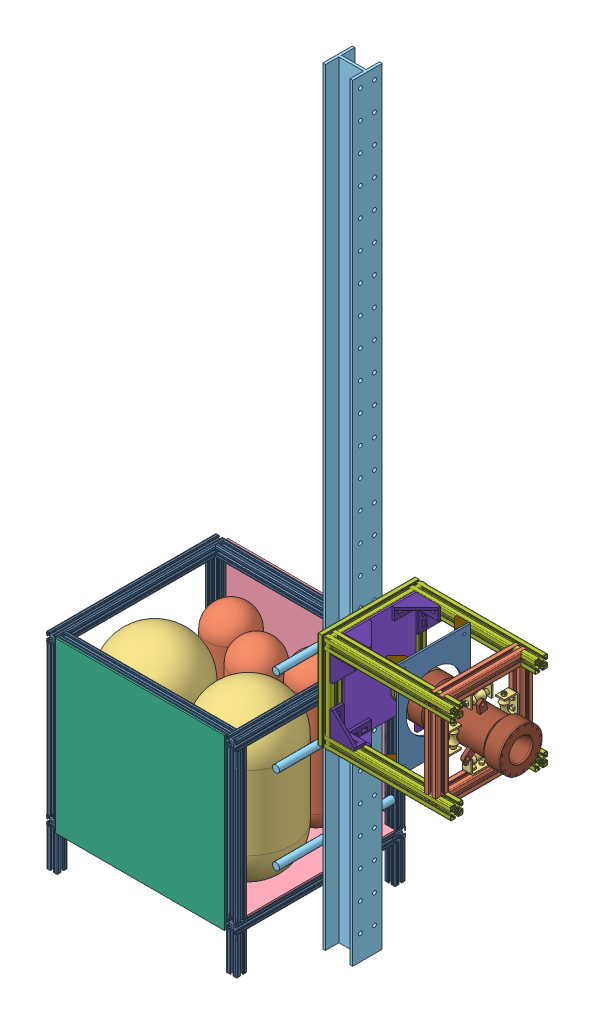
SolidWorks assembly test stand assembly 2, configuration Default. Lengths in mm.
Overall size (1639.33 2768.6 927.95).
43 component instances, 22 part files, 94 mates.
Components (placement in the parent):
- tank stand frame 2.4-1: tank stand frame 2.4 [Default<As Machined>] at (-191.008 152.4 280.9875) x (1 0 0) z (0 -1 0) size (1130.3 921.62 742.94)
- propellant tank 2.0-1: propellant tank 2.0 [Default] at (-514.846 688.2063 -114.5341) x (-0.562986 0 -0.826467) z (0.826467 0 -0.562986) size (165.1 533.4 165.1)
- propellant tank 1.0-1: propellant tank 1.0 [Default] at (-346.571 725.2175 84.1255) x (0.999065 0 0.043239) z (-0.043239 0 0.999065) size (317.5 584.2 317.5)
- propellant tank 1.0-2: propellant tank 1.0 [Default] at (-683.121 725.2175 84.1255) x (0.998919 0 0.046481) z (-0.046481 0 0.998919) size (317.5 584.2 317.5)
- right mounting plate 2.0-1: right mounting plate 2.0 [Default] at (-210.046 133.362 -315.9005) size (609.6 609.6 6.35)
- FAR_Ibeam_medium-1: FAR_Ibeam_medium [Default] x (0 0 -1) z (1 0 0) size (419.1 2768.6 133.35)
- left mounting plate 2.0-1: left mounting plate 2.0 [Default] at (-210.046 133.362 300.0255) size (609.6 609.6 6.35)
- engine stand frame 2.0-1: engine stand frame 2.0 [Default<As Machined>] at (22.5 779.0293 -147.087) x (0 0 -1) z (1 0 0) size (349.8 349.8 479.7)
- back engine mounting plate 2.0-1: back engine mounting plate 2.0 [Default] at (45 756.5293 -124.587) x (0 0 -1) z (1 0 0) size (259.8 349.8 6.35)
- load cell-1: load cell [Default] at (51.35 906.0293 -4.212) size (76.2 50.8 19.05)
- cooling channel engine 4-1: cooling channel engine 4 [Default] at (232.325 931.4293 5.313) x (0 0.98875 0.149576) z (0 -0.149576 0.98875) size (176.52 431.77 177.16)
  - pintle anulus plate_4-1: pintle anulus plate_4 [Default] at (0 -6.35 0) size (98.42 25.4 98.42)
  - slot cooling jacket 6.1-1: slot cooling jacket 6.1 [Default] at origin size (176.52 333.35 177.16)
  - dome_4-1: dome_4 [Default] at (0 6.35 0) size (152.4 73.03 152.4)
  - pintle4-1: pintle4 [Default] at (0 79.375 0) x (0.94067 0 0.339322) z (-0.339322 0 0.94067) size (25.4 101.6 25.4)
  - pintle sleve4-1: pintle sleve4 [Default] at (0 49.0371 0) size (38.1 64.29 38.1)
  - pintle holder insert 4-1: pintle holder insert 4 [Default] at (0 66.675 0) x (0.998275 0 0.058716) z (-0.058716 0 0.998275) size (50.8 12.7 50.8)
  - pintle lox connector4-1: pintle lox connector4 [Default] at (0 79.375 0) size (101.6 25.4 101.6)
- 80-20 large L bracket-1: 80-20 large L bracket [Default] at (45 801.5293 180.213) x (-1 0 0) z (0 -1 0) size (88 42 88)
- 80-20 large L bracket-2: 80-20 large L bracket [Default] at (45 756.5293 -124.587) x (0 1 0) z (-1 0 0) size (88 42 88)
- 80-20 large L bracket-3: 80-20 large L bracket [Default] at (45 1061.3293 -169.587) x (-1 0 0) z (0 1 0) size (88 42 88)
- 80-20 large L bracket-4: 80-20 large L bracket [Default] at (45 1061.3293 180.213) x (0 1 0) z (-1 0 0) size (88 42 88)
- 80-20 large L bracket-5: 80-20 large L bracket [Default] at (51.35 756.5293 -169.587) x (-1 0 0) z (0 0 -1) size (88 42 88)
- 80-20 large L bracket-6: 80-20 large L bracket [Default] at (51.35 756.5293 135.213) x (0 0 1) z (-1 0 0) size (88 42 88)
- 80-20 large L bracket-7: 80-20 large L bracket [Default] at (51.35 1106.3293 135.213) x (-1 0 0) z (0 0 1) size (88 42 88)
- 80-20 large L bracket-8: 80-20 large L bracket [Default] at (51.35 1106.3293 -124.587) x (0 0 -1) z (-1 0 0) size (88 42 88)
- 80-20 45mm small L bracket-5: 80-20 45mm small L bracket [Default] at (24 801.5293 -124.587) x (0 0 -1) z (1 0 0) size (42 42 42)
- 80-20 45mm small L bracket-6: 80-20 45mm small L bracket [Default] at (24 1061.3293 -124.587) x (0 1 0) z (1 0 0) size (42 42 42)
- 80-20 45mm small L bracket-7: 80-20 45mm small L bracket [Default] at (24 1061.3293 135.213) x (0 0 1) z (1 0 0) size (42 42 42)
- 80-20 45mm small L bracket-8: 80-20 45mm small L bracket [Default] at (24 801.5293 135.213) x (0 -1 0) z (1 0 0) size (42 42 42)
- engine holder 2.1-2: engine holder 2.1 [Default] at (246.853 756.5293 135.213) x (0 0 1) z (-1 0 0) size (259.8 349.8 6.35)
- 80-20 45mm small L bracket-9: 80-20 45mm small L bracket [Default] at (240.503 1085.3293 -124.587) x (0 0 -1) z (0 1 0) size (42 42 42)
- 80-20 45mm small L bracket-10: 80-20 45mm small L bracket [Default] at (240.503 1085.3293 135.213) x (0 0 1) z (0 -1 0) size (42 42 42)
- 80-20 45mm small L bracket-11: 80-20 45mm small L bracket [Default] at (240.503 777.5293 -124.587) x (0 0 -1) z (0 1 0) size (42 42 42)
- 80-20 45mm small L bracket-12: 80-20 45mm small L bracket [Default] at (240.503 777.5293 135.213) x (1 0 0) z (0 1 0) size (42 42 42)
- roller mounting bars 2.3-1: roller mounting bars 2.3 [Default<As Machined>] at (406.4 1083.8293 157.713) x (0 1 0) z (0 0 1) size (349.8 45 349.8)
- 6581N11_Roller Support-1: 6581N11_Roller Support [6581N11] at (406.4 820.5793 9.1848) x (0 0 -1) z (1 0 0) size (101.6 86.68 31.75)
- 6581N11_Roller Support-2: 6581N11_Roller Support [6581N11] at (406.4 1042.2793 9.1848) x (0 0 1) z (1 0 0) size (101.6 86.68 31.75)
- 6581N11_Roller Support-3: 6581N11_Roller Support [6581N11] at (406.4 942.4003 -105.537) x (0 1 0) z (1 0 0) size (101.6 86.68 31.75)
- 6581N11_Roller Support-4: 6581N11_Roller Support [6581N11] at (406.4 942.4003 116.163) x (0 -1 0) z (1 0 0) size (101.6 86.68 31.75)
- lower tank plate 2.4-1: lower tank plate 2.4 [Default] at (-210.046 171.438 261.9255) size (685.8 6.35 609.6)
- propellant tank 2.0-2: propellant tank 2.0 [Default] at (-361.532 688.2063 -175.7943) size (165.1 533.4 165.1)
- propellant tank 2.0-3: propellant tank 2.0 [Default] at (-668.1601 688.2063 -175.7943) size (165.1 533.4 165.1)
Mates (geometry in assembly coordinates):
- Coincident23: coincident aligned: plane of right mounting plate 2.0-1 through (-210.046 133.362 -309.5505) normal (1 0 0); plane of left mounting plate 2.0-1 through (-210.046 133.362 306.3755) normal (1 0 0)
- Coincident24: coincident aligned: plane of right mounting plate 2.0-1 through (-210.046 133.362 -309.5505) normal (0 -1 0); plane of left mounting plate 2.0-1 through (-210.046 133.362 306.3755) normal (0 -1 0)
- Concentric8: concentric anti-aligned: cylinder of back engine mounting plate 2.0-1 through (51.35 931.4293 5.313) axis (1 0 0) radius 6.5481; cylinder of load cell-1 through (51.35 931.4293 5.313) axis (-1 0 0) radius 6.5481
- Coincident29: coincident anti-aligned: plane of back engine mounting plate 2.0-1 through (51.35 756.5293 -124.587) normal (1 0 0); plane of load cell-1 through (51.35 906.0293 14.838) normal (-1 0 0)
- Concentric9: concentric anti-aligned: cylinder of load cell-1 through (127.55 931.4293 5.313) axis (1 0 0) radius 6.5481; cylinder of cooling channel engine 4-1/pintle lox connector4-1 through (127.55 931.4293 5.313) axis (-1 0 0) radius 8.9281
- Coincident31: coincident anti-aligned: plane of load cell-1 through (127.55 956.8293 14.838) normal (1 0 0); plane of cooling channel engine 4-1/pintle lox connector4-1 through (127.55 931.4293 5.313) normal (-1 0 0)
- Coincident37: coincident anti-aligned: plane of engine stand frame 2.0-1 through (45 1083.8293 176.588) normal (1 0 0); plane of 80-20 large L bracket-1 through (45 889.5293 138.213) normal (-1 0 0)
- Coincident38: coincident anti-aligned: plane of engine stand frame 2.0-1 through (479.7 801.5293 176.588) normal (0 1 0); plane of 80-20 large L bracket-1 through (45 801.5293 138.213) normal (0 -1 0)
- Coincident39: coincident aligned: plane of engine stand frame 2.0-1 through (479.7 785.2563 180.213) normal (0 0 1); plane of 80-20 large L bracket-1 through (45 801.5293 180.213) normal (0 0 1)
- Coincident40: coincident anti-aligned: plane of engine stand frame 2.0-1 through (45 779.0293 -165.962) normal (1 0 0); plane of 80-20 large L bracket-2 through (45 756.5293 -166.587) normal (-1 0 0)
- Coincident41: coincident anti-aligned: plane of engine stand frame 2.0-1 through (22.5 756.5293 -153.314) normal (0 -1 0); plane of 80-20 large L bracket-2 through (133 756.5293 -166.587) normal (0 1 0)
- Coincident42: coincident aligned: plane of engine stand frame 2.0-1 through (22.5 772.8023 -124.587) normal (0 0 1); plane of 80-20 large L bracket-2 through (45 756.5293 -124.587) normal (0 0 1)
- Coincident43: coincident aligned: plane of engine stand frame 2.0-1 through (28.727 1106.3293 -147.087) normal (0 1 0); plane of back engine mounting plate 2.0-1 through (51.35 1106.3293 135.213) normal (0 1 0)
- Coincident44: coincident anti-aligned: plane of engine stand frame 2.0-1 through (45 1102.7043 -147.087) normal (1 0 0); plane of back engine mounting plate 2.0-1 through (45 756.5293 -124.587) normal (-1 0 0)
- Coincident45: coincident anti-aligned: plane of engine stand frame 2.0-1 through (479.7 1102.7043 -124.587) normal (0 0 1); plane of back engine mounting plate 2.0-1 through (51.35 1106.3293 -124.587) normal (0 0 -1)
- Distance4: distance = 127 mm aligned: plane of engine stand frame 2.0-1 through (3.625 1083.8293 180.213) normal (0 0 1); plane of FAR_Ibeam_medium-1 through (0 2768.6 53.213) normal (0 0 1)
- Coincident50: coincident anti-aligned: plane of FAR_Ibeam_medium-1 through (0 2768.6 -53.213) normal (1 0 0); plane of engine stand frame 2.0-1 through (0 1090.0563 -147.087) normal (-1 0 0)
- Coincident53: coincident anti-aligned: plane of engine stand frame 2.0-1 through (22.5 1061.3293 151.486) normal (0 -1 0); plane of 80-20 large L bracket-4 through (133 1061.3293 138.213) normal (0 1 0)
- Coincident54: coincident anti-aligned: plane of engine stand frame 2.0-1 through (45 1083.8293 176.588) normal (1 0 0); plane of 80-20 large L bracket-4 through (45 1061.3293 138.213) normal (-1 0 0)
- Coincident55: coincident aligned: plane of engine stand frame 2.0-1 through (28.727 1083.8293 180.213) normal (0 0 1); plane of 80-20 large L bracket-4 through (45 1061.3293 180.213) normal (0 0 1)
- Coincident56: coincident anti-aligned: plane of engine stand frame 2.0-1 through (479.7 1061.3293 -128.212) normal (0 -1 0); plane of 80-20 large L bracket-3 through (45 1061.3293 -127.587) normal (0 1 0)
- Coincident57: coincident anti-aligned: plane of engine stand frame 2.0-1 through (45 779.0293 -165.962) normal (1 0 0); plane of 80-20 large L bracket-3 through (45 973.3293 -127.587) normal (-1 0 0)
- Coincident58: coincident aligned: plane of engine stand frame 2.0-1 through (28.727 779.0293 -169.587) normal (0 0 -1); plane of 80-20 large L bracket-3 through (45 1061.3293 -169.587) normal (0 0 -1)
- Coincident71: coincident anti-aligned: plane of engine stand frame 2.0-1 through (22.5 1090.0563 135.213) normal (0 0 -1); plane of 80-20 large L bracket-7 through (51.35 1064.3293 135.213) normal (0 0 1)
- Coincident72: coincident aligned: plane of back engine mounting plate 2.0-1 through (51.35 1106.3293 135.213) normal (0 1 0); plane of 80-20 large L bracket-7 through (51.35 1106.3293 135.213) normal (0 1 0)
- Coincident73: coincident anti-aligned: plane of back engine mounting plate 2.0-1 through (51.35 756.5293 -124.587) normal (1 0 0); plane of 80-20 large L bracket-7 through (51.35 1064.3293 47.213) normal (-1 0 0)
- Coincident74: coincident aligned: plane of back engine mounting plate 2.0-1 through (51.35 1106.3293 135.213) normal (0 1 0); plane of 80-20 large L bracket-8 through (51.35 1106.3293 -124.587) normal (0 1 0)
- Coincident75: coincident anti-aligned: plane of engine stand frame 2.0-1 through (479.7 1102.7043 -124.587) normal (0 0 1); plane of 80-20 large L bracket-8 through (139.35 1064.3293 -124.587) normal (0 0 -1)
- Coincident76: coincident anti-aligned: plane of back engine mounting plate 2.0-1 through (51.35 756.5293 -124.587) normal (1 0 0); plane of 80-20 large L bracket-8 through (51.35 1064.3293 -124.587) normal (-1 0 0)
- Coincident77: coincident anti-aligned: plane of engine stand frame 2.0-1 through (479.7 797.9043 135.213) normal (0 0 -1); plane of 80-20 large L bracket-6 through (139.35 798.5293 135.213) normal (0 0 1)
- Coincident78: coincident anti-aligned: plane of back engine mounting plate 2.0-1 through (51.35 756.5293 -124.587) normal (1 0 0); plane of 80-20 large L bracket-6 through (51.35 798.5293 135.213) normal (-1 0 0)
- Coincident79: coincident aligned: plane of back engine mounting plate 2.0-1 through (51.35 756.5293 -124.587) normal (0 -1 0); plane of 80-20 large L bracket-6 through (51.35 756.5293 135.213) normal (0 -1 0)
- Coincident80: coincident aligned: plane of back engine mounting plate 2.0-1 through (51.35 756.5293 -124.587) normal (0 -1 0); plane of 80-20 large L bracket-5 through (51.35 756.5293 -169.587) normal (0 -1 0)
- Coincident81: coincident anti-aligned: plane of back engine mounting plate 2.0-1 through (51.35 756.5293 -124.587) normal (1 0 0); plane of 80-20 large L bracket-5 through (51.35 798.5293 -81.587) normal (-1 0 0)
- Coincident82: coincident aligned: plane of engine stand frame 2.0-1 through (22.5 760.1543 -169.587) normal (0 0 -1); plane of 80-20 large L bracket-5 through (51.35 798.5293 -169.587) normal (0 0 -1)
- Coincident83: coincident anti-aligned: plane of engine stand frame 2.0-1 through (16.273 779.0293 -124.587) normal (0 0 1); plane of 80-20 45mm small L bracket-6 through (45 1061.3293 -124.587) normal (0 0 -1)
- Coincident84: coincident anti-aligned: plane of engine stand frame 2.0-1 through (16.273 1061.3293 -147.087) normal (0 -1 0); plane of 80-20 45mm small L bracket-6 through (45 1061.3293 -82.587) normal (0 1 0)
- Coincident85: coincident anti-aligned: plane of back engine mounting plate 2.0-1 through (45 756.5293 -124.587) normal (-1 0 0); plane of 80-20 45mm small L bracket-6 through (45 1061.3293 -124.587) normal (1 0 0)
- Coincident86: coincident anti-aligned: plane of engine stand frame 2.0-1 through (16.273 779.0293 -124.587) normal (0 0 1); plane of 80-20 45mm small L bracket-5 through (45 843.5293 -124.587) normal (0 0 -1)
- Coincident87: coincident anti-aligned: plane of engine stand frame 2.0-1 through (16.273 801.5293 157.713) normal (0 1 0); plane of 80-20 45mm small L bracket-5 through (45 801.5293 -124.587) normal (0 -1 0)
- Coincident88: coincident anti-aligned: plane of back engine mounting plate 2.0-1 through (45 756.5293 -124.587) normal (-1 0 0); plane of 80-20 45mm small L bracket-5 through (45 801.5293 -124.587) normal (1 0 0)
- Coincident89: coincident anti-aligned: plane of engine stand frame 2.0-1 through (16.273 1061.3293 -147.087) normal (0 -1 0); plane of 80-20 45mm small L bracket-7 through (45 1061.3293 135.213) normal (0 1 0)
- Coincident90: coincident anti-aligned: plane of engine stand frame 2.0-1 through (16.273 1083.8293 135.213) normal (0 0 -1); plane of 80-20 45mm small L bracket-7 through (45 1019.3293 135.213) normal (0 0 1)
- Coincident91: coincident anti-aligned: plane of back engine mounting plate 2.0-1 through (45 756.5293 -124.587) normal (-1 0 0); plane of 80-20 45mm small L bracket-7 through (45 1061.3293 135.213) normal (1 0 0)
- Coincident92: coincident anti-aligned: plane of engine stand frame 2.0-1 through (16.273 801.5293 157.713) normal (0 1 0); plane of 80-20 45mm small L bracket-8 through (45 801.5293 93.213) normal (0 -1 0)
- Coincident93: coincident anti-aligned: plane of engine stand frame 2.0-1 through (16.273 1083.8293 135.213) normal (0 0 -1); plane of 80-20 45mm small L bracket-8 through (45 801.5293 135.213) normal (0 0 1)
- Coincident94: coincident anti-aligned: plane of back engine mounting plate 2.0-1 through (45 756.5293 -124.587) normal (-1 0 0); plane of 80-20 45mm small L bracket-8 through (45 801.5293 135.213) normal (1 0 0)
- Coincident96: coincident aligned: plane of engine stand frame 2.0-1 through (22.5 1106.3293 163.94) normal (0 1 0); plane of engine holder 2.1-2 through (240.503 1106.3293 -124.587) normal (0 1 0)
- Coincident98: coincident aligned: plane of engine holder 2.1-2 through (240.503 1106.3293 -124.587) normal (0 1 0); plane of 80-20 45mm small L bracket-9 through (240.503 1106.3293 -124.587) normal (0 1 0)
- Coincident99: coincident anti-aligned: plane of engine holder 2.1-2 through (240.503 756.5293 135.213) normal (-1 0 0); plane of 80-20 45mm small L bracket-9 through (240.503 1106.3293 -124.587) normal (1 0 0)
- Coincident100: coincident aligned: plane of engine holder 2.1-2 through (240.503 1106.3293 -124.587) normal (0 1 0); plane of 80-20 45mm small L bracket-10 through (240.503 1106.3293 135.213) normal (0 1 0)
- Coincident101: coincident aligned: plane of engine holder 2.1-2 through (240.503 1106.3293 135.213) normal (0 0 1); plane of 80-20 45mm small L bracket-10 through (198.503 1064.3293 135.213) normal (0 0 1)
- Coincident102: coincident anti-aligned: plane of engine holder 2.1-2 through (240.503 756.5293 135.213) normal (-1 0 0); plane of 80-20 45mm small L bracket-10 through (240.503 1064.3293 135.213) normal (1 0 0)
- Coincident103: coincident aligned: plane of engine holder 2.1-2 through (240.503 756.5293 135.213) normal (0 -1 0); plane of 80-20 45mm small L bracket-12 through (240.503 756.5293 135.213) normal (0 -1 0)
- Coincident104: coincident anti-aligned: plane of engine holder 2.1-2 through (240.503 756.5293 135.213) normal (-1 0 0); plane of 80-20 45mm small L bracket-12 through (240.503 798.5293 93.213) normal (1 0 0)
- Coincident105: coincident aligned: plane of engine holder 2.1-2 through (240.503 1106.3293 135.213) normal (0 0 1); plane of 80-20 45mm small L bracket-12 through (240.503 798.5293 135.213) normal (0 0 1)
- Coincident106: coincident aligned: plane of engine holder 2.1-2 through (240.503 756.5293 135.213) normal (0 -1 0); plane of 80-20 45mm small L bracket-11 through (240.503 756.5293 -124.587) normal (0 -1 0)
- Coincident107: coincident anti-aligned: plane of engine holder 2.1-2 through (240.503 756.5293 135.213) normal (-1 0 0); plane of 80-20 45mm small L bracket-11 through (240.503 798.5293 -124.587) normal (1 0 0)
- Coincident108: coincident aligned: plane of engine holder 2.1-2 through (240.503 756.5293 -124.587) normal (0 0 -1); plane of 80-20 45mm small L bracket-11 through (198.503 798.5293 -124.587) normal (0 0 -1)
- Coincident110: coincident aligned: plane of engine stand frame 2.0-1 through (479.7 756.5293 163.94) normal (0 -1 0); plane of roller mounting bars 2.3-1 through (425.275 756.5293 -147.087) normal (0 -1 0)
- Coincident111: coincident anti-aligned: plane of roller mounting bars 2.3-1 through (387.525 801.5293 -147.087) normal (0 1 0); plane of 6581N11_Roller Support-1 through (422.275 801.5293 -19.7394) normal (0 -1 0)
- Symmetric1: symmetric aligned: plane of roller mounting bars 2.3-1 through (406.4 1083.8293 157.713) normal (-1 0 0); plane of 6581N11_Roller Support-1 through (422.275 811.6106 38.1091) normal (1 0 0); plane of 6581N11_Roller Support-1 through (390.525 811.6106 38.1091) normal (-1 0 0)
- Coincident113: coincident anti-aligned: plane of roller mounting bars 2.3-1 through (412.627 1083.8293 -124.587) normal (0 0 1); plane of 6581N11_Roller Support-3 through (422.275 971.3245 -124.587) normal (0 0 -1)
- Coincident114: coincident aligned: plane of 6581N11_Roller Support-1 through (422.275 811.6106 38.1091) normal (1 0 0); plane of 6581N11_Roller Support-3 through (422.275 913.476 -114.5057) normal (1 0 0)
- Coincident115: coincident anti-aligned: plane of roller mounting bars 2.3-1 through (387.525 1061.3293 157.713) normal (0 -1 0); plane of 6581N11_Roller Support-2 through (422.275 1061.3293 38.1091) normal (0 1 0)
- Coincident116: coincident aligned: plane of 6581N11_Roller Support-2 through (422.275 1051.2481 -19.7394) normal (1 0 0); plane of 6581N11_Roller Support-3 through (422.275 913.476 -114.5057) normal (1 0 0)
- Coincident117: coincident aligned: plane of 6581N11_Roller Support-1 through (422.275 811.6106 38.1091) normal (1 0 0); plane of 6581N11_Roller Support-4 through (422.275 971.3245 125.1317) normal (1 0 0)
- Coincident118: coincident anti-aligned: plane of roller mounting bars 2.3-1 through (412.627 779.0293 135.213) normal (0 0 -1); plane of 6581N11_Roller Support-4 through (422.275 913.476 135.213) normal (0 0 1)
- Coincident119: coincident aligned: plane of 6581N11_Roller Support-1 through (422.275 811.6106 48.1903) normal (0 0 1); plane of 6581N11_Roller Support-2 through (422.275 1008.9418 48.1903) normal (0 0 1)
- Coincident120: coincident aligned: plane of 6581N11_Roller Support-3 through (422.275 903.3948 -114.5057) normal (0 -1 0); plane of 6581N11_Roller Support-4 through (422.275 903.3948 82.8255) normal (0 -1 0)
- Coincident121: coincident aligned: plane of engine holder 2.1-2 through (240.503 756.5293 -124.587) normal (0 0 -1); plane of 80-20 45mm small L bracket-9 through (198.503 1106.3293 -124.587) normal (0 0 -1)
- Coincident122: coincident anti-aligned: plane of engine stand frame 2.0-1 through (479.7 1102.7043 -124.587) normal (0 0 1); plane of engine holder 2.1-2 through (240.503 756.5293 -124.587) normal (0 0 -1)
- Coincident123: coincident aligned: plane of engine stand frame 2.0-1 through (22.5 1102.7043 180.213) normal (0 0 1); plane of roller mounting bars 2.3-1 through (400.173 779.0293 180.213) normal (0 0 1)
- Distance5: distance = 50.8 mm aligned: plane of roller mounting bars 2.3-1 through (428.9 1090.0563 157.713) normal (1 0 0); plane of engine stand frame 2.0-1 through (479.7 1100.1523 -156.76) normal (1 0 0)
- Coincident124: coincident anti-aligned: plane of FAR_Ibeam_medium-1 through (0 0 0) normal (0 0 -1)
- Coincident125: coincident aligned: plane of FAR_Ibeam_medium-1 through (0 0 0) normal (1 0 0)
- Coincident126: coincident aligned: plane of FAR_Ibeam_medium-1 through (0 0 0) normal (0 1 0)
- Distance6: distance = 76.2 mm anti-aligned: plane of tank stand frame 2.4-1 through (-184.15 726.6353 -290.5125) normal (1 0 0); plane of FAR_Ibeam_medium-1 through (-107.95 2768.6 53.213) normal (-1 0 0)
- Distance7: distance = 304.8 mm aligned: plane of tank stand frame 2.4-1 through (-193.7433 712.2922 -309.5625) normal (0 0 -1); plane of FAR_Ibeam_medium-1 through (-98.425 2768.6 -4.7625) normal (0 0 -1)
- Coincident129: coincident aligned: plane of tank stand frame 2.4-1 through (-193.7433 0 -278.9047) normal (0 -1 0); plane of FAR_Ibeam_medium-1 through (0 0 0) normal (0 -1 0)
- Coincident131: coincident: line of tank stand frame 2.4-1 through (-210.046 707.7494 -309.5505) axis (-1 0 0); plane of right mounting plate 2.0-1 through (-210.046 133.362 -309.5505) normal (0 0 1)
- Coincident132: coincident: line of tank stand frame 2.4-1 through (-210.046 707.7494 300.0255) axis (-1 0 0); plane of left mounting plate 2.0-1 through (-210.046 133.362 300.0255) normal (0 0 -1)
- Parallel1: parallel anti-aligned: line of tank stand frame 2.4-1 through (-171.97 704.862 297.1381) axis (0 -1 0); line of left mounting plate 2.0-1 through (-210.046 133.362 306.3755) axis (0 1 0)
- Coincident134: coincident: line of tank stand frame 2.4-1 through (-207.1586 171.438 280.9875) axis (0 0 -1); plane of lower tank plate 2.4-1 through (-210.046 171.438 261.9255) normal (0 -1 0)
- Coincident135: coincident: line of tank stand frame 2.4-1 through (-822.5574 171.438 -290.5125) axis (0 0 1); plane of lower tank plate 2.4-1 through (-210.046 171.438 261.9255) normal (0 -1 0)
- Coincident136: coincident: line of tank stand frame 2.4-1 through (-210.046 168.5506 300.0255) axis (-1 0 0); plane of lower tank plate 2.4-1 through (-210.046 177.788 300.0255) normal (0 0 1)
- Coincident137: coincident: sphere of propellant tank 1.0-2; circle of lower tank plate 2.4-1
- Coincident138: coincident: sphere of propellant tank 1.0-1; circle of lower tank plate 2.4-1
- Coincident139: coincident: sphere of propellant tank 2.0-1; circle of lower tank plate 2.4-1
- Coincident140: coincident: circle of lower tank plate 2.4-1; sphere of propellant tank 2.0-2
- Coincident141: coincident: circle of lower tank plate 2.4-1; sphere of propellant tank 2.0-3
- Coincident142: coincident: line of tank stand frame 2.4-1 through (-857.746 168.5506 -290.5125) axis (0 0 1); plane of lower tank plate 2.4-1 through (-857.746 177.788 261.9255) normal (-1 0 0)
- Distance8: distance = 38.1 mm: line of tank stand frame 2.4-1 through (-857.746 704.862 297.1381) axis (0 -1 0); plane of left mounting plate 2.0-1 through (-819.646 133.362 306.3755) normal (-1 0 0)
- Coincident144: coincident: line of tank stand frame 2.4-1 through (-207.1586 133.362 297.1381) axis (-1 0 0); plane of left mounting plate 2.0-1 through (-210.046 133.362 306.3755) normal (0 -1 0)
